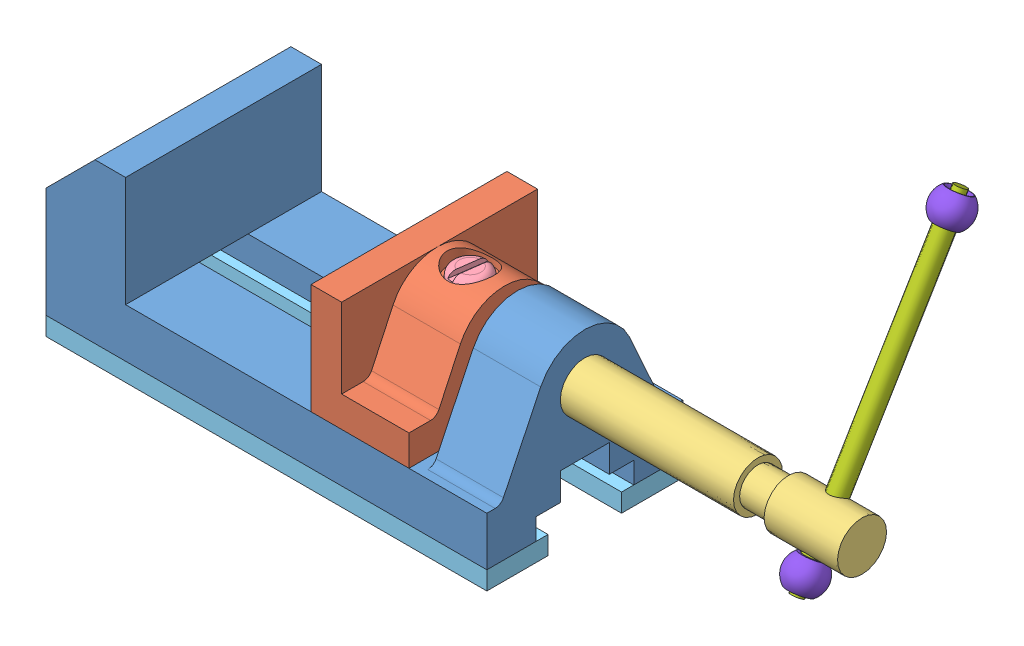
SolidWorks assembly vice_assembly, configuration Default. Lengths in mm.
Overall size (234.57 119.15 93.6).
16 component instances, 9 part files, 36 mates.
Components (placement in the parent):
- vice_part1-1: vice_part1 [Default] at (-20.6804 -17.3721 5.0511) size (144 52 85.59)
- vice_part2-1: vice_part2 [Default] at (9.8849 -1.3721 5.0511) x (0 0 -1) z (1 0 0) size (64 45 32)
- vice_part6-1: vice_part6 [Default] at (58.6568 18.6279 5.0511) x (1 0 0) z (0 -0.514327 -0.857594) size (138 16 16)
- M6x1x7_flathead-1: M6x1x7_flathead [Default] at (13.8849 29.3846 5.0511) x (-0.134625 0 0.990897) z (-0.990897 0 -0.134625) size (12 12.07 12)
- vice_part3-1: vice_part3 [Default] at (-20.6804 -17.3721 -16.9489) x (-1 0 0) z (0 0 1) size (144 6 29.24)
- vice_part3-2: vice_part3 [Default] at (-20.6804 -17.3721 27.0511) x (-1 0 0) z (0 0 1) size (144 6 29.24)
- vice_part7-1: vice_part7 [Default] at (9.8849 -10.3721 5.0511) x (-1 0 0) z (0 0 1) size (32 7 32)
- vice_part4-2: vice_part4 [Default] at (129.8849 83.8051 -34.0378) x (0 -0.857594 0.514327) z (-0.742649 -0.344435 -0.574315) size (104 6 6)
- vice_part5-1: vice_part5 [Default] at (129.8849 87.6643 -36.3522) x (0 0.857594 -0.514327) z (-0.528439 -0.436649 -0.728073) size (9 12 12)
- vice_part5-2: vice_part5 [Default] at (129.8849 7.908 11.4802) x (0 -0.857594 0.514327) z (0.76091 -0.333725 -0.556457) size (9 12 12)
- M6x1x16_flathead-1: M6x1x16_flathead [Default] at (-56.6804 -19.3427 27.0511) x (-0.240383 0 -0.970678) z (-0.970678 0 0.240383) size (10.73 17.73 10.9)
- M6x1x16_flathead-2: M6x1x16_flathead [Default] at (13.3196 -19.3427 -16.9489) x (-0.240383 0 -0.970678) z (-0.970678 0 0.240383) size (10.73 17.73 10.9)
- M6x1x16_flathead-4: M6x1x16_flathead [Default] at (13.3196 -19.3427 27.0511) x (-0.13322 0 0.991086) z (0.991086 0 0.13322) size (10.73 17.73 10.9)
- M6x1x16_flathead-5: M6x1x16_flathead [Default] at (-56.6804 -19.3427 -16.9489) x (-0.240383 0 -0.970678) z (-0.970678 0 0.240383) size (10.73 17.73 10.9)
- M6x1x16_flathead-6: M6x1x16_flathead [Default] at (17.8849 -13.3427 5.0511) x (0.030784 0 -0.999526) z (-0.999526 0 -0.030784) size (10.73 17.73 10.9)
- M6x1x16_flathead-7: M6x1x16_flathead [Default] at (1.8849 -13.3427 5.0511) x (0.030784 0 -0.999526) z (-0.999526 0 -0.030784) size (10.73 17.73 10.9)
Mates (geometry in assembly coordinates):
- Coincident11: coincident: plane of assembly; plane of assembly; plane of vice_part1-1 through (-92.6814 -10.3721 -2.9489) normal (0 0 1); plane of vice_part2-1 through (-24.4726 -10.3721 -2.9489) normal (0 0 -1)
- Coincident21: coincident: plane of assembly; plane of assembly; plane of vice_part1-1 through (-20.6804 -1.3721 5.0511) normal (0 1 0); plane of vice_part2-1 through (9.8849 -1.3721 5.0511) normal (0 -1 0)
- Parallel11: parallel: plane of assembly; plane of assembly; plane of vice_part1-1 through (-66.6804 34.6279 -26.9489) normal (1 0 0); plane of vice_part2-1 through (-6.1151 8.6279 -26.9489) normal (-1 0 0)
- Concentric2: concentric: cylinder of assembly; cylinder of assembly; cylinder of vice_part1-1 through (29.3196 18.6279 5.0511) axis (1 0 0) radius 8; cylinder of vice_part6-1 through (3.8849 18.6279 5.0511) axis (-1 0 0) radius 8
- Coincident5: coincident: plane of assembly; plane of assembly; plane of vice_part2-1 through (25.8849 8.6279 -26.9489) normal (1 0 0); plane of vice_part6-1 through (25.8849 21.7139 10.1966) normal (-1 0 0)
- Coincident6: coincident: plane of assembly; plane of assembly; plane of vice_part2-1 through (13.8849 30.2479 1.5511) normal (0 1 0); plane of M6x1x7_flathead-1 through (10.9122 30.2479 4.6472) normal (0 -1 0)
- LimitDistance2: limit distance = 60.5653 mm: plane of assembly; plane of assembly; plane of vice_part2-1 through (-6.1151 8.6279 -26.9489) normal (-1 0 0); plane of vice_part1-1 through (-66.6804 34.6279 -26.9489) normal (1 0 0)
- Concentric3: concentric: cylinder of assembly; cone of assembly; cylinder of vice_part1-1 through (-56.6804 -17.3721 -16.9489) axis (0 -1 0) radius 3.125; cone of vice_part3-1 through (-56.6804 -23.3721 -16.9489) axis (0 1 0)
- Coincident22: coincident: plane of assembly; plane of assembly; plane of vice_part1-1 through (-20.6804 -17.3721 5.0511) normal (0 -1 0); plane of vice_part3-1 through (-20.6804 -17.3721 -16.9489) normal (0 1 0)
- Concentric5: concentric: cylinder of assembly; cone of assembly; cylinder of vice_part1-1 through (13.3196 -17.3721 -16.9489) axis (0 -1 0) radius 3.125; cone of vice_part3-1 through (13.3196 -23.3721 -16.9489) axis (0 1 0)
- Concentric6: concentric: cylinder of assembly; cone of assembly; cylinder of vice_part1-1 through (13.3196 -17.3721 27.0511) axis (0 -1 0) radius 3.125; cone of vice_part3-2 through (13.3196 -23.3721 27.0511) axis (0 1 0)
- Coincident23: coincident: plane of assembly; plane of assembly; plane of vice_part1-1 through (-20.6804 -17.3721 5.0511) normal (0 -1 0); plane of vice_part3-2 through (-20.6804 -17.3721 27.0511) normal (0 1 0)
- Concentric8: concentric: circle of assembly; cone of assembly; circle of vice_part1-1; cone of vice_part3-2 through (-56.6804 -23.3721 27.0511) axis (0 1 0)
- Concentric9: concentric: cylinder of assembly; cone of assembly; cylinder of vice_part2-1 through (17.8849 -10.3721 5.0511) axis (0 -1 0) radius 2.5; cone of vice_part7-1 through (17.8849 -14.3721 5.0511) axis (0 1 0)
- Concentric10: concentric: circle of assembly; cone of assembly; circle of vice_part2-1; cone of vice_part7-1 through (1.8849 -17.3721 5.0511) axis (0 1 0)
- Coincident26: coincident: plane of assembly; plane of assembly; plane of vice_part2-1 through (-24.4726 -10.3721 13.0511) normal (0 -1 0); plane of vice_part7-1 through (9.8849 -10.3721 5.0511) normal (0 1 0)
- Concentric12: concentric: cylinder of assembly; cylinder of assembly; cylinder of vice_part6-1 through (129.8849 25.4895 0.9359) axis (0 -0.857594 0.514327) radius 3; cylinder of vice_part4-2 through (129.8849 11.7672 9.1657) axis (0 0.857594 -0.514327) radius 3
- Concentric13: concentric: circle of assembly; circle of assembly; circle of vice_part4-2; circle of vice_part5-1
- Coincident27: coincident: plane of assembly; plane of assembly; plane of vice_part4-2 through (129.8849 83.8051 -34.0378) normal (0 0.857594 -0.514327); plane of vice_part5-1 through (118.163 83.8522 -33.9592) normal (0 -0.857594 0.514327)
- Concentric14: concentric: circle of assembly; circle of assembly; circle of vice_part4-2; circle of vice_part5-2
- Coincident29: coincident: plane of assembly; plane of assembly; plane of vice_part4-2 through (129.8849 11.7672 9.1657) normal (0 -0.857594 0.514327); plane of vice_part5-2 through (141.0277 13.6395 12.2876) normal (0 0.857594 -0.514327)
- LimitDistance3: limit distance = 0 mm: plane of assembly; line of assembly; plane of vice_part5-2 through (141.0277 13.6395 12.2876) normal (0 0.857594 -0.514327); line of vice_part6-1 through (118.0703 11.7672 9.1657) axis (1 0 0)
- Concentric15: concentric: circle of assembly; circle of assembly; circle of vice_part2-1; circle of M6x1x7_flathead-1
- Concentric18: concentric: circle of assembly; cone of assembly; circle of vice_part3-2; cone of M6x1x16_flathead-1 through (-56.6804 -22.5221 27.0511) axis (0 1 0)
- Coincident33: coincident: cone of assembly; cone of assembly; cone of vice_part3-2 through (-56.6804 -23.3721 27.0511) axis (0 1 0); cone of M6x1x16_flathead-1 through (-56.6804 -22.5221 27.0511) axis (0 1 0)
- Concentric19: concentric: cone of assembly; cone of assembly; cone of vice_part3-1 through (13.3196 -23.3721 -16.9489) axis (0 1 0); cone of M6x1x16_flathead-2 through (13.3196 -22.5221 -16.9489) axis (0 1 0)
- Coincident35: coincident: cone of assembly; cone of assembly; cone of vice_part3-1 through (13.3196 -23.3721 -16.9489) axis (0 1 0); cone of M6x1x16_flathead-2 through (13.3196 -22.5221 -16.9489) axis (0 1 0)
- Concentric22: concentric: circle of assembly; cone of assembly; circle of vice_part3-2; cone of M6x1x16_flathead-4 through (13.3196 -22.5221 27.0511) axis (0 1 0)
- Coincident40: coincident: cone of assembly; cone of assembly; cone of vice_part3-2 through (13.3196 -23.3721 27.0511) axis (0 1 0); cone of M6x1x16_flathead-4 through (13.3196 -22.5221 27.0511) axis (0 1 0)
- Concentric23: concentric: circle of assembly; cone of assembly; circle of vice_part3-1; cone of M6x1x16_flathead-5 through (-56.6804 -22.5221 -16.9489) axis (0 1 0)
- Coincident42: coincident: cone of assembly; cone of assembly; cone of vice_part3-1 through (-56.6804 -23.3721 -16.9489) axis (0 1 0); cone of M6x1x16_flathead-5 through (-56.6804 -22.5221 -16.9489) axis (0 1 0)
- LimitDistance5: limit distance = 3.4347 mm: plane of assembly; plane of assembly; plane of vice_part2-1 through (25.8849 8.6279 -26.9489) normal (1 0 0); plane of vice_part1-1 through (29.3196 18.6279 5.0511) normal (-1 0 0)
- Concentric24: concentric: circle of assembly; cone of assembly; circle of vice_part7-1; cone of M6x1x16_flathead-6 through (17.8849 -16.5221 5.0511) axis (0 1 0)
- Coincident44: coincident: cone of assembly; cone of assembly; cone of vice_part7-1 through (17.8849 -17.3721 5.0511) axis (0 1 0); cone of M6x1x16_flathead-6 through (17.8849 -16.5221 5.0511) axis (0 1 0)
- Concentric25: concentric: circle of assembly; cone of assembly; circle of vice_part7-1; cone of M6x1x16_flathead-7 through (1.8849 -16.5221 5.0511) axis (0 1 0)
- Coincident46: coincident: cone of assembly; cone of assembly; cone of vice_part7-1 through (1.8849 -17.3721 5.0511) axis (0 1 0); cone of M6x1x16_flathead-7 through (1.8849 -16.5221 5.0511) axis (0 1 0)
